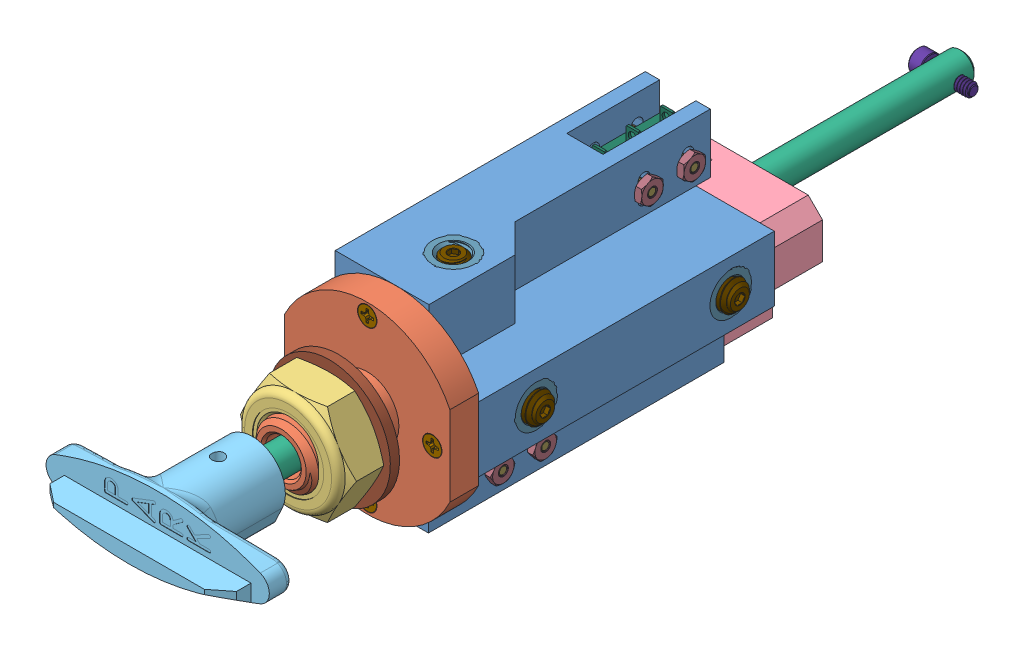
SolidWorks assembly Parking Brake Handle Mechanism, configuration Stowed. Lengths in mm.
Overall size (49.4 44.55 184.53).
50 component instances, 18 part files, 77 mates.
Components (placement in the parent):
- Parking Brake Mechanism Body-1: Parking Brake Mechanism Body [Default] at (0 0 49.2125) x (-1 0 0) z (0 0 -1) size (39.75 43.81 68.58)
- Wing Fold Mechanism Upper Cap-1: Wing Fold Mechanism Upper Cap [Default] at (0 0 -19.177) size (36.58 40.64 28.08)
- Wing Fold Handle Retaining Nut-1: Wing Fold Handle Retaining Nut [Default] at (0 0 -17.145) size (25.66 23.83 11.45)
- Parking Brake Mechanism End Cap-1: Parking Brake Mechanism End Cap [Default] at (0 0 -29.0195) x (-1 0 0) z (0 0 -1) size (39.75 30.68 10.67)
- Parking Brake Handle-1: Parking Brake Handle [Default] at (0 0 6.0325) x (0 1 0) z (0 0 1) size (15.42 49.4 27.31)
- Parking Brake Mechanism Shaft-3: Parking Brake Mechanism Shaft [Default] at (0 0 -46.0375) x (0 -1 0) z (0 0 1) size (6.35 6.35 176.28)
- 6338K411-1: 6338K411 [Default] at (0 0 36.3855) x (1 0 0) z (0 -1 0) size (12.7 6.35 12.7)
- 6338K411-2: 6338K411 [Default] at (0 0 -39.6875) x (-0.923728 -0.383049 0) z (-0.383049 0.923728 0) size (12.7 6.35 12.7)
- 93365A112-14: 93365A112 [Default] at (0 -11.1125 42.7355) x (1 0 0) z (0 -1 0) size (3.58 4.78 3.58)
- 93365A112-15: 93365A112 [Default] at (0 17.68 36.3855) x (1 0 0) z (0 -1 0) size (3.58 4.78 3.58)
- 93365A112-16: 93365A112 [Default] at (14.378 0 36.3855) x (1 0 0) z (0 -1 0) size (3.58 4.78 3.58)
- 93365A112-17: 93365A112 [Default] at (0 -17.68 36.3855) x (1 0 0) z (0 -1 0) size (3.58 4.78 3.58)
- 93365A112-18: 93365A112 [Default] at (-14.378 0 36.3855) x (1 0 0) z (0 -1 0) size (3.58 4.78 3.58)
- 93365A112-12: 93365A112 [Default] at (12.3825 0 -29.0195) x (-0.923728 -0.383049 0) z (0.383049 -0.923728 0) size (3.58 4.78 3.58)
- 93365A112-13: 93365A112 [Default] at (-15.8591 0 -29.0195) x (-0.85131 -0.524663 0) z (0.524663 -0.85131 0) size (3.58 4.78 3.58)
- 93365A112-19: 93365A112 [Default] at (0 -18.5166 -29.0195) x (-0.85131 -0.524663 0) z (0.524663 -0.85131 0) size (3.58 4.78 3.58)
- 96640A027-9: 96640A027 [Default] at (-14.378 0 41.4401) size (4.11 4.11 12.73)
- 96640A027-10: 96640A027 [Default] at (0 -17.68 41.4401) size (4.11 4.11 12.73)
- 96640A027-11: 96640A027 [Default] at (0 17.68 41.4401) size (4.11 4.11 12.73)
- 96640A027-12: 96640A027 [Default] at (14.378 0 41.4401) size (4.11 4.11 12.73)
- 96640A025-1: 96640A025 [Default] at (0 -11.1125 47.7901) size (4.11 4.11 9.56)
- 96640A027-5: 96640A027 [Default] at (12.3825 0 -35.6489) x (0.628171 -0.778076 0) z (0 0 -1) size (4.11 4.11 12.73)
- 96640A027-6: 96640A027 [Default] at (-15.8591 0 -35.6489) x (0.743591 -0.668635 0) z (0 0 -1) size (4.11 4.11 12.73)
- 96640A027-8: 96640A027 [Default] at (0 -6.0071 75.7643) x (-0.410756 0 -0.911745) z (0 -1 0) size (4.11 4.11 12.73)
- 96640A027-13: 96640A027 [Default] at (0 -18.5166 -35.6489) x (0.995409 0.095714 0) z (0 0 -1) size (4.11 4.11 12.73)
- 92141A034-1: 92141A034 [Default] at (0 0 49.0855) x (1 0 0) z (0 -1 0) size (26.97 2.03 26.97)
- 91249A060 - PHS, 2-56 X .625, 18-8, BLACK OXIDE-10: 91249A060 - PHS, 2-56 X .625, 18-8, BLACK OXIDE [91249A060] at (8.6868 -18.2683 21.3928) x (0 0 -1) z (-1 0 0) size (4.24 4.24 17.48)
- 91249A060 - PHS, 2-56 X .625, 18-8, BLACK OXIDE-9: 91249A060 - PHS, 2-56 X .625, 18-8, BLACK OXIDE [91249A060] at (8.6868 -18.2683 12.0329) x (0 0.158553 -0.987351) z (-1 0 0) size (4.24 4.24 17.48)
- 91249A060 - PHS, 2-56 X .625, 18-8, BLACK OXIDE-13: 91249A060 - PHS, 2-56 X .625, 18-8, BLACK OXIDE [91249A060] at (-18.2683 8.6868 21.3928) x (-0.143817 0 0.989604) z (0 -1 0) size (4.24 4.24 17.48)
- 91249A060 - PHS, 2-56 X .625, 18-8, BLACK OXIDE-8: 91249A060 - PHS, 2-56 X .625, 18-8, BLACK OXIDE [91249A060] at (-18.2683 8.6868 12.0329) x (-0.33861 0 0.940927) z (0 -1 0) size (4.24 4.24 17.48)
- 91249A060 - PHS, 2-56 X .625, 18-8, BLACK OXIDE-14: 91249A060 - PHS, 2-56 X .625, 18-8, BLACK OXIDE [91249A060] at (2.4447 12.3755 -27.1886) x (0 0.421154 -0.906989) z (-1 0 0) size (4.24 4.24 17.48)
- 91249A060 - PHS, 2-56 X .625, 18-8, BLACK OXIDE-12: 91249A060 - PHS, 2-56 X .625, 18-8, BLACK OXIDE [91249A060] at (2.4447 12.3755 -17.8287) x (0 0.429957 -0.902849) z (-1 0 0) size (4.24 4.24 17.48)
- 91841A003-5: 91841A003 [Default] at (7.9819 -18.2683 21.3928) x (0 -1 0) z (0 0 1) size (4.76 1.72 5.5)
- 91841A003-7: 91841A003 [Default] at (7.9819 -18.2683 12.0329) x (0 -0.987351 -0.158553) z (0 -0.158553 0.987351) size (4.76 1.72 5.5)
- 91841A003-9: 91841A003 [Default] at (-18.2683 7.9819 21.3928) x (-0.989604 0 -0.143817) z (0.143817 0 -0.989604) size (4.76 1.72 5.5)
- 91841A003-11: 91841A003 [Default] at (-18.2683 7.9819 12.0329) x (-0.940927 0 -0.33861) z (0.33861 0 -0.940927) size (4.76 1.72 5.5)
- 91841A003-13: 91841A003 [Default] at (1.7399 12.3755 -27.1886) x (0 -0.906989 -0.421154) z (0 -0.421154 0.906989) size (4.76 1.72 5.5)
- 91841A003-15: 91841A003 [Default] at (1.7399 12.3755 -17.8287) x (0 -0.902849 -0.429957) z (0 -0.429957 0.902849) size (4.76 1.72 5.5)
- 93365A160 - INSERT, .25-20, BRASS, FOR PLASTICS-1: 93365A160 - INSERT, .25-20, BRASS, FOR PLASTICS [93365A160] at (18.288 0 -19.3675) x (0 0.381849 -0.924225) z (0 -0.924225 -0.381849) size (9.53 8.41 9.53)
- 93365A160 - INSERT, .25-20, BRASS, FOR PLASTICS-2: 93365A160 - INSERT, .25-20, BRASS, FOR PLASTICS [93365A160] at (18.288 0 23.6855) x (0 0.523557 -0.85199) z (0 -0.85199 -0.523557) size (9.53 8.41 9.53)
- 93365A160 - INSERT, .25-20, BRASS, FOR PLASTICS-4: 93365A160 - INSERT, .25-20, BRASS, FOR PLASTICS [93365A160] at (0 20.32 23.6855) x (-0.834128 0 -0.551571) z (0.551571 0 -0.834128) size (9.53 8.41 9.53)
- 7658K15-1: 7658K15 [Clipped] at (0 -20.6305 16.6049) x (0 0 1) z (-1 0 0) size (19.99 17.27 6.5)
- 7658K15-2: 7658K15 [Clipped] at (-6.242 14.7377 -22.4007) x (0 0 -1) z (-1 0 0) size (19.99 17.27 6.5)
- 7658K15-3: 7658K15 [Clipped] at (-20.6305 0 16.6049) x (0 0 1) z (0 1 0) size (19.99 17.27 6.5)
- 90176A102 - SPACER, UNTHREADED, .125 X #8 X .250, NYLON 6, BLACK-1: 90176A102 - SPACER, UNTHREADED, .125 X #8 X .250, NYLON 6, BLACK [94639A201] at (-4.7625 0 -25.7175) x (0 0.978585 -0.205844) z (1 0 0) size (6.35 6.35 3.17)
- 91251A108 - SHCS, 4-40 x .375, STEEL, BLACK-OXIDE-1: 91251A108 - SHCS, 4-40 x .375, STEEL, BLACK-OXIDE [91251A108] at (3.175 0 -25.7175) x (0 -0.927315 -0.374281) z (1 0 0) size (4.65 4.65 12.74)
- 91251A108 - SHCS, 4-40 x .375, STEEL, BLACK-OXIDE-2: 91251A108 - SHCS, 4-40 x .375, STEEL, BLACK-OXIDE [91251A108] at (6.35 0 -85.0646) x (0 -0.898283 -0.439417) z (1 0 0) size (4.65 4.65 12.74)
- 5901A142 - SPRING PLUNGER, .25-20 X .625 BODY, .125 X .035 NOSE, 3-7LBS FORCE, STEEL, BLACK-1: 5901A142 - SPRING PLUNGER, .25-20 X .625 BODY, .125 X .035 NOSE, 3-7LBS FORCE, STEEL, BLACK [5901A142] at (0 11.7475 23.6855) x (1 0 0) z (0 0 -1) size (6.42 18.35 6.4)
- 5901A142 - SPRING PLUNGER, .25-20 X .625 BODY, .125 X .035 NOSE, 3-7LBS FORCE, STEEL, BLACK-2: 5901A142 - SPRING PLUNGER, .25-20 X .625 BODY, .125 X .035 NOSE, 3-7LBS FORCE, STEEL, BLACK [5901A142] at (11.7475 0 23.6855) x (0 -1 0) z (0 0 -1) size (6.42 18.35 6.4)
- 5901A142 - SPRING PLUNGER, .25-20 X .625 BODY, .125 X .035 NOSE, 3-7LBS FORCE, STEEL, BLACK-3: 5901A142 - SPRING PLUNGER, .25-20 X .625 BODY, .125 X .035 NOSE, 3-7LBS FORCE, STEEL, BLACK [5901A142] at (11.7475 0 -19.3675) x (0 -1 0) z (0 0 -1) size (6.42 18.35 6.4)
Mates (geometry in assembly coordinates):
- Concentric43: concentric anti-aligned: cylinder of Parking Brake Mechanism Shaft-3 through (0 0 87.1855) axis (0 0 -1) radius 3.175; cylinder of Parking Brake Handle-1 through (0 0 68.1355) axis (0 0 1) radius 3.2385
- Concentric44: concentric aligned: cylinder of Parking Brake Mechanism Shaft-3 through (0 -3.175 75.7643) axis (0 -1 0) radius 0.889; cylinder of Parking Brake Handle-1 through (0 -7.3025 75.7643) axis (0 -1 0) radius 1.3526
- Concentric45: concentric anti-aligned: cylinder of Parking Brake Mechanism Shaft-3 through (-3.175 0 -25.7175) axis (-1 0 0) radius 1.1303; cylinder of 91251A108 - SHCS, 4-40 x .375, STEEL, BLACK-OXIDE-1 through (-9.1948 0 -25.7175) axis (1 0 0) radius 2.3241
- Tangent1: tangent aligned: cylinder of Parking Brake Mechanism Shaft-3 through (0 0 87.1855) axis (0 0 -1) radius 3.175; plane of 91251A108 - SHCS, 4-40 x .375, STEEL, BLACK-OXIDE-1 through (3.175 0 -25.7175) normal (1 0 0)
- Coincident71: coincident anti-aligned: plane of 7658K15-1 through (0 -20.6305 16.6049) normal (-1 0 0); plane of assembly through (0 0 0) normal (1 0 0)
- Distance2: distance = 20.6305 mm aligned: plane of 7658K15-1 through (0 -20.6305 16.6049) normal (0 1 0); plane of assembly through (0 0 0) normal (0 1 0)
- Coincident83: coincident aligned: plane of 7658K15-3 through (-20.6305 0 16.6049) normal (0 1 0); plane of assembly through (0 0 0) normal (0 1 0)
- Coincident84: coincident: plane of 7658K15-1 through (-3.2512 -11.3595 6.61) normal (0 0 -1); plane of 7658K15-3 through (-11.3595 3.2512 6.61) normal (0 0 -1)
- Distance6: distance = 20.6305 mm aligned: plane of 7658K15-3 through (-20.6305 0 16.6049) normal (1 0 0); plane of assembly through (0 0 0) normal (1 0 0)
- Coincident86: coincident aligned: plane of 5901A142 - SPRING PLUNGER, .25-20 X .625 BODY, .125 X .035 NOSE, 3-7LBS FORCE, STEEL, BLACK-1 through (0 11.7475 23.6855) normal (1 0 0); plane of assembly through (0 0 0) normal (1 0 0)
- Tangent3: tangent anti-aligned: cylinder of Parking Brake Mechanism Shaft-3 through (0 0 87.1855) axis (0 0 -1) radius 3.175; plane of 5901A142 - SPRING PLUNGER, .25-20 X .625 BODY, .125 X .035 NOSE, 3-7LBS FORCE, STEEL, BLACK-1 through (0 3.175 23.6855) normal (0 -1 0)
- Concentric47: concentric anti-aligned: cylinder of 91251A108 - SHCS, 4-40 x .375, STEEL, BLACK-OXIDE-1 through (-9.1948 0 -25.7175) axis (1 0 0) radius 2.3241; cylinder of 90176A102 - SPACER, UNTHREADED, .125 X #8 X .250, NYLON 6, BLACK-1 through (-3.175 0 -25.7175) axis (-1 0 0) radius 1.4605
- Coincident87: coincident anti-aligned: plane of 91251A108 - SHCS, 4-40 x .375, STEEL, BLACK-OXIDE-1 through (-6.35 0 -25.7175) normal (1 0 0); plane of 90176A102 - SPACER, UNTHREADED, .125 X #8 X .250, NYLON 6, BLACK-1 through (-6.35 0 -25.7175) normal (-1 0 0)
- Coincident88: coincident aligned: plane of 5901A142 - SPRING PLUNGER, .25-20 X .625 BODY, .125 X .035 NOSE, 3-7LBS FORCE, STEEL, BLACK-1 through (0 11.7475 23.6855) normal (0 0 -1); plane of 5901A142 - SPRING PLUNGER, .25-20 X .625 BODY, .125 X .035 NOSE, 3-7LBS FORCE, STEEL, BLACK-2 through (11.7475 0 23.6855) normal (0 0 -1)
- Coincident89: coincident anti-aligned: plane of 5901A142 - SPRING PLUNGER, .25-20 X .625 BODY, .125 X .035 NOSE, 3-7LBS FORCE, STEEL, BLACK-2 through (11.7475 0 23.6855) normal (0 -1 0); plane of assembly through (0 0 0) normal (0 1 0)
- Tangent4: tangent anti-aligned: cylinder of Parking Brake Mechanism Shaft-3 through (0 0 87.1855) axis (0 0 -1) radius 3.175; plane of 5901A142 - SPRING PLUNGER, .25-20 X .625 BODY, .125 X .035 NOSE, 3-7LBS FORCE, STEEL, BLACK-2 through (3.175 0 23.6855) normal (-1 0 0)
- Coincident91: coincident: line of Parking Brake Mechanism Body-1; line of 7658K15-2 through (-7.3469 3.302 -20.3306) axis (1 0 0)
- Coincident92: coincident aligned: plane of 5901A142 - SPRING PLUNGER, .25-20 X .625 BODY, .125 X .035 NOSE, 3-7LBS FORCE, STEEL, BLACK-2 through (11.7475 0 23.6855) normal (-1 0 0); plane of 5901A142 - SPRING PLUNGER, .25-20 X .625 BODY, .125 X .035 NOSE, 3-7LBS FORCE, STEEL, BLACK-3 through (11.7475 0 -19.3675) normal (-1 0 0)
- Coincident93: coincident aligned: plane of 5901A142 - SPRING PLUNGER, .25-20 X .625 BODY, .125 X .035 NOSE, 3-7LBS FORCE, STEEL, BLACK-2 through (11.7475 0 23.6855) normal (0 -1 0); plane of 5901A142 - SPRING PLUNGER, .25-20 X .625 BODY, .125 X .035 NOSE, 3-7LBS FORCE, STEEL, BLACK-3 through (11.7475 0 -19.3675) normal (0 -1 0)
- Concentric49: concentric: cylinder of assembly; cylinder of Parking Brake Mechanism Body-1 through (0 0 -39.6875) axis (0 0 -1) radius 4.7879; cylinder of 6338K411-2 through (0 0 -33.3375) axis (0 0 -1) radius 4.7625
- Coincident95: coincident: plane of Parking Brake Mechanism Body-1 through (0 0 -39.6875) normal (0 0 -1); plane of 6338K411-2 through (0 0 -39.6875) normal (0 0 -1)
- Concentric50: concentric anti-aligned: cylinder of Parking Brake Mechanism Shaft-3 through (-3.175 0 -85.0646) axis (-1 0 0) radius 1.1303; cylinder of 91251A108 - SHCS, 4-40 x .375, STEEL, BLACK-OXIDE-2 through (-6.0198 0 -85.0646) axis (1 0 0) radius 2.3241
- Tangent5: tangent anti-aligned: cylinder of Parking Brake Mechanism Shaft-3 through (0 0 87.1855) axis (0 0 -1) radius 3.175; plane of 91251A108 - SHCS, 4-40 x .375, STEEL, BLACK-OXIDE-2 through (-3.175 0 -85.0646) normal (1 0 0)
- Concentric51: concentric anti-aligned: cone of Parking Brake Mechanism Body-1 through (12.3825 0 -29.0195) axis (0 0 1); cylinder of 93365A112-12 through (12.3825 0 -29.0195) axis (0 0 -1) radius 1.6116
- Coincident96: coincident aligned: plane of Parking Brake Mechanism Body-1 through (0 0 -29.0195) normal (0 0 -1); plane of 93365A112-12 through (14.0366 0.6859 -29.0195) normal (0 0 -1)
- Concentric52: concentric anti-aligned: cylinder of Parking Brake Mechanism Body-1 through (-15.8591 0 -29.0195) axis (0 0 1) radius 76.9753; cylinder of 93365A112-13 through (-15.8591 0 -29.0195) axis (0 0 -1) radius 1.6116
- Coincident97: coincident aligned: plane of Parking Brake Mechanism Body-1 through (0 0 -29.0195) normal (0 0 -1); plane of 93365A112-13 through (-14.3347 0.9395 -29.0195) normal (0 0 -1)
- Concentric57: concentric aligned: cylinder of 91249A060 - PHS, 2-56 X .625, 18-8, BLACK OXIDE-10 through (8.6868 -18.2683 21.3928) axis (1 0 0) radius 2.1209; cylinder of 7658K15-1 through (-3.2512 -18.2683 21.3928) axis (1 0 0) radius 1.1049
- Coincident101: coincident: plane of 91249A060 - PHS, 2-56 X .625, 18-8, BLACK OXIDE-10 through (-7.1882 -18.2683 21.3928) normal (1 0 0); plane of Parking Brake Mechanism Body-1 through (-7.1882 92.3005 -39.6875) normal (-1 0 0)
- Concentric59: concentric aligned: circle of 91249A060 - PHS, 2-56 X .625, 18-8, BLACK OXIDE-10; unknown of 91841A003-5
- Coincident102: coincident anti-aligned: plane of 91841A003-5 through (7.1882 -15.8871 20.018) normal (-1 0 0); plane of Parking Brake Mechanism Body-1 through (7.1882 92.3005 55.5625) normal (1 0 0)
- Concentric60: concentric: cylinder of 91249A060 - PHS, 2-56 X .625, 18-8, BLACK OXIDE-9 through (8.6868 -18.2683 12.0329) axis (1 0 0) radius 2.1209; unknown of 91841A003-7
- Concentric61: concentric aligned: cylinder of 7658K15-1 through (-3.2512 -18.2683 12.0329) axis (1 0 0) radius 1.1049; cylinder of 91249A060 - PHS, 2-56 X .625, 18-8, BLACK OXIDE-9 through (8.6868 -18.2683 12.0329) axis (1 0 0) radius 2.1209
- Coincident103: coincident anti-aligned: plane of Parking Brake Mechanism Body-1 through (-7.1882 92.3005 -39.6875) normal (-1 0 0); plane of 91249A060 - PHS, 2-56 X .625, 18-8, BLACK OXIDE-9 through (-7.1882 -18.2683 12.0329) normal (1 0 0)
- Coincident104: coincident anti-aligned: plane of Parking Brake Mechanism Body-1 through (7.1882 92.3005 55.5625) normal (1 0 0); plane of 91841A003-7 through (7.1882 -15.6992 11.053) normal (-1 0 0)
- Concentric63: concentric: cylinder of 91249A060 - PHS, 2-56 X .625, 18-8, BLACK OXIDE-13 through (-18.2683 8.6868 21.3928) axis (0 1 0) radius 2.1209; unknown of 91841A003-9
- Concentric64: concentric anti-aligned: cylinder of 7658K15-3 through (-18.2683 3.2512 21.3928) axis (0 -1 0) radius 1.1049; cylinder of 91249A060 - PHS, 2-56 X .625, 18-8, BLACK OXIDE-13 through (-18.2683 8.6868 21.3928) axis (0 1 0) radius 2.1209
- Coincident105: coincident anti-aligned: plane of Parking Brake Mechanism Body-1 through (-3.683 -7.1882 5.848) normal (0 -1 0); plane of 91249A060 - PHS, 2-56 X .625, 18-8, BLACK OXIDE-13 through (-18.2683 -7.1882 21.3928) normal (0 1 0)
- Coincident106: coincident anti-aligned: plane of Parking Brake Mechanism Body-1 through (-3.683 7.1882 27.3618) normal (0 1 0); plane of 91841A003-9 through (-16.1095 7.1882 23.0958) normal (0 -1 0)
- Concentric66: concentric: cylinder of 91249A060 - PHS, 2-56 X .625, 18-8, BLACK OXIDE-8 through (-18.2683 8.6868 12.0329) axis (0 1 0) radius 2.1209; unknown of 91841A003-11
- Concentric67: concentric anti-aligned: cylinder of 7658K15-3 through (-18.2683 3.2512 12.0329) axis (0 -1 0) radius 1.1049; cylinder of 91249A060 - PHS, 2-56 X .625, 18-8, BLACK OXIDE-8 through (-18.2683 8.6868 12.0329) axis (0 1 0) radius 2.1209
- Coincident107: coincident anti-aligned: plane of Parking Brake Mechanism Body-1 through (-3.683 -7.1882 5.848) normal (0 -1 0); plane of 91249A060 - PHS, 2-56 X .625, 18-8, BLACK OXIDE-8 through (-18.2683 -7.1882 12.0329) normal (0 1 0)
- Coincident108: coincident anti-aligned: plane of Parking Brake Mechanism Body-1 through (-3.683 7.1882 27.3618) normal (0 1 0); plane of 91841A003-11 through (-16.4933 7.1882 14.1328) normal (0 -1 0)
- Concentric69: concentric: cylinder of 91249A060 - PHS, 2-56 X .625, 18-8, BLACK OXIDE-10 through (8.6868 -18.2683 21.3928) axis (1 0 0) radius 2.1209; unknown of 91841A003-13
- Concentric70: concentric aligned: cylinder of 7658K15-2 through (-9.4932 12.3755 -27.1886) axis (1 0 0) radius 1.1049; cylinder of 91249A060 - PHS, 2-56 X .625, 18-8, BLACK OXIDE-10 through (8.6868 -18.2683 21.3928) axis (1 0 0) radius 2.1209
- Coincident109: coincident anti-aligned: plane of Parking Brake Mechanism Body-1 through (-13.4302 -92.8026 55.5625) normal (-1 0 0); plane of 91249A060 - PHS, 2-56 X .625, 18-8, BLACK OXIDE-14 through (-13.4302 12.3755 -27.1886) normal (1 0 0)
- Coincident110: coincident anti-aligned: plane of Parking Brake Mechanism Body-1 through (0.9461 -92.8026 -39.6875) normal (1 0 0); plane of 91841A003-13 through (0.9461 15.1143 -27.4327) normal (-1 0 0)
- Coincident111: coincident anti-aligned: plane of Parking Brake Mechanism Body-1 through (-13.4302 -92.8026 55.5625) normal (-1 0 0); plane of 91249A060 - PHS, 2-56 X .625, 18-8, BLACK OXIDE-12 through (-13.4302 12.3755 -17.8287) normal (1 0 0)
- Coincident112: coincident anti-aligned: plane of Parking Brake Mechanism Body-1 through (0.9461 -92.8026 -39.6875) normal (1 0 0); plane of 91841A003-15 through (0.9461 15.1165 -18.0461) normal (-1 0 0)
- Concentric75: concentric anti-aligned: cylinder of Parking Brake Mechanism Body-1 through (18.288 0 -19.3675) axis (-1 0 0) radius 23.3291; cylinder of 93365A160 - INSERT, .25-20, BRASS, FOR PLASTICS-1 through (18.288 0 -19.3675) axis (1 0 0) radius 4.4323
- Coincident113: coincident aligned: plane of Parking Brake Mechanism Body-1 through (18.288 8.8573 -39.6875) normal (1 0 0); plane of 93365A160 - INSERT, .25-20, BRASS, FOR PLASTICS-1 through (18.288 0 -19.3675) normal (1 0 0)
- Concentric76: concentric anti-aligned: cylinder of Parking Brake Mechanism Body-1 through (18.288 0 23.6855) axis (-1 0 0) radius 23.3291; cylinder of 93365A160 - INSERT, .25-20, BRASS, FOR PLASTICS-2 through (18.288 0 23.6855) axis (1 0 0) radius 4.4323
- Coincident114: coincident aligned: plane of Parking Brake Mechanism Body-1 through (18.288 8.8573 -39.6875) normal (1 0 0); plane of 93365A160 - INSERT, .25-20, BRASS, FOR PLASTICS-2 through (18.288 0 23.6855) normal (1 0 0)
- Concentric77: concentric anti-aligned: cylinder of Parking Brake Mechanism Body-1 through (0 20.32 23.6855) axis (0 -1 0) radius 23.3291; cylinder of 93365A160 - INSERT, .25-20, BRASS, FOR PLASTICS-4 through (0 20.32 23.6855) axis (0 1 0) radius 4.4323
- Coincident115: coincident aligned: plane of Parking Brake Mechanism Body-1 through (0 20.32 -39.6875) normal (0 1 0); plane of 93365A160 - INSERT, .25-20, BRASS, FOR PLASTICS-4 through (0 20.32 23.6855) normal (0 1 0)
- Concentric78: concentric aligned: cylinder of Parking Brake Handle-1 through (0 -7.3025 75.7643) axis (0 1 0) radius 715.585; cylinder of 96640A027-8 through (0 -7.3025 75.7643) axis (0 1 0) radius 715.585
- Tangent6: tangent aligned: cylinder of Parking Brake Handle-1 through (0 54.0707 89.0905) axis (0 0 -1) radius 61.3732; plane of 96640A027-8 through (0 -7.3025 75.7643) normal (0 -1 0)
- Concentric80: concentric aligned: cylinder of Parking Brake Mechanism Shaft-3 through (0 0 87.1855) axis (0 0 -1) radius 3.175; cylinder of Parking Brake Mechanism Body-1 through (0 0 49.2125) axis (0 0 -1) radius 4.7625
- Concentric81: concentric aligned: cylinder of Parking Brake Mechanism Shaft-3 through (0 0 87.1855) axis (0 0 -1) radius 3.175; cylinder of Parking Brake Mechanism Body-1 through (0 0 49.2125) axis (0 0 -1) radius 4.7625
- Parallel15: parallel: plane of assembly; plane of assembly; plane of Parking Brake Mechanism Body-1 through (0 -23.495 -39.6875) normal (0 -1 0); plane of Parking Brake Handle-1 through (0 0 92.2655) normal (0 1 0); plane of assembly; plane of assembly; plane of Wing Fold Mechanism Upper Cap-1; plane of Parking Brake Handle-1
- Parallel16: parallel: plane of Wing Fold Mechanism Upper Cap-1 through (-18.288 8.8573 36.3855) normal (-1 0 0); plane of Parking Brake Handle-1 through (0 0 92.2655) normal (0 1 0)
- Concentric82: concentric anti-aligned: cylinder of Parking Brake Mechanism Shaft-3 through (0 0 87.1855) axis (0 0 -1) radius 3.175; cylinder of Wing Fold Mechanism Upper Cap-1 through (0 0 42.7355) axis (0 0 1) radius 3.9688
- LimitAngle3: limit planar angle = 1.570796 rad anti-aligned: plane of Wing Fold Mechanism Upper Cap-1 through (18.288 -8.8573 36.3855) normal (1 0 0); plane of Parking Brake Handle-1 through (0 0 92.2655) normal (0 1 0)
- Perpendicular3: perpendicular: plane of Wing Fold Mechanism Upper Cap-1 through (-18.288 8.8573 36.3855) normal (-1 0 0); plane of Parking Brake Handle-1 through (0 0 92.2655) normal (0 1 0)
- Coincident119: coincident: plane of Wing Fold Mechanism Upper Cap-1 through (0 0 36.3855) normal (0 0 -1); plane of Parking Brake Mechanism Body-1 through (0 0 36.3855) normal (0 0 1)
- Parallel17: parallel: plane of Wing Fold Mechanism Upper Cap-1 through (18.288 -8.8573 36.3855) normal (1 0 0); plane of Parking Brake Mechanism Body-1 through (18.288 8.8573 -39.6875) normal (1 0 0)
- LimitDistance3: limit distance = 19.05 mm aligned: plane of Parking Brake Handle-1 through (0 0 68.1355) normal (0 0 -1); plane of 92141A034-1 through (0 0 49.0855) normal (0 0 -1)
- Distance15: distance = 19.05 mm: plane of Parking Brake Handle-1 through (0 0 68.1355) normal (0 0 -1); plane of 92141A034-1 through (0 0 49.0855) normal (0 0 -1)
- Distance16: distance = 87.63 mm: plane of 5901A142 - SPRING PLUNGER, .25-20 X .625 BODY, .125 X .035 NOSE, 3-7LBS FORCE, STEEL, BLACK-3 through (11.7475 0 -19.3675) normal (0 0 -1); plane of 92141A034-1 through (0 0 49.0855) normal (0 0 -1)
- InPlace1: in place: plane of Parking Brake Mechanism Body-1 through (0 0 -29.0195) normal (0 0 -1); plane of Parking Brake Mechanism End Cap-1 through (0 0 -29.0195) normal (0 0 -1); moOrthogonalPlaneRef_w of Parking Brake Mechanism Body-1 through (0 0 -29.0195) normal (0 0 -1); plane of Parking Brake Mechanism End Cap-1 through (0 0 -29.0195) normal (0 1 0); plane of Parking Brake Mechanism Body-1 through (0 0 -29.0195) normal (0 0 -1); plane of Parking Brake Mechanism End Cap-1 through (0 0 -29.0195) normal (-1 0 0); plane of Parking Brake Mechanism Body-1 through (0 0 -29.0195) normal (0 0 -1); unknown of Parking Brake Mechanism End Cap-1
- Coincident120: coincident aligned: plane of Parking Brake Mechanism Body-1; plane of Parking Brake Mechanism End Cap-1
- Coincident121: coincident aligned: plane of Parking Brake Mechanism Body-1 through (0 0 -29.0195) normal (0 1 0); plane of Parking Brake Mechanism End Cap-1 through (0 0 -29.0195) normal (0 1 0)
- Coincident122: coincident anti-aligned: plane of Parking Brake Mechanism Body-1 through (0 0 -29.0195) normal (1 0 0); plane of Parking Brake Mechanism End Cap-1 through (0 0 -29.0195) normal (-1 0 0)
- Concentric83: concentric aligned: cylinder of Parking Brake Mechanism Body-1 through (0 -18.5166 -29.0195) axis (0 0 1) radius 76.9753; cylinder of 93365A112-19 through (0 -18.5166 -27.3959) axis (0 0 1) radius 297.135
- Coincident120: coincident aligned: plane of Parking Brake Mechanism Body-1 through (0 0 -29.0195) normal (0 0 -1); plane of 93365A112-19 through (1.5244 -17.5771 -29.0195) normal (0 0 -1)
- Concentric84: concentric aligned: cylinder of Parking Brake Mechanism End Cap-1 through (0 -18.5166 -36.9443) axis (0 0 1) radius 715.585; cylinder of 96640A027-13 through (0 -18.5166 -36.9443) axis (0 0 1) radius 715.585
- Coincident121: coincident aligned: plane of 96640A027-5 through (12.3825 0 -36.9443) normal (0 0 -1); plane of 96640A027-13 through (0 -18.5166 -36.9443) normal (0 0 -1)
